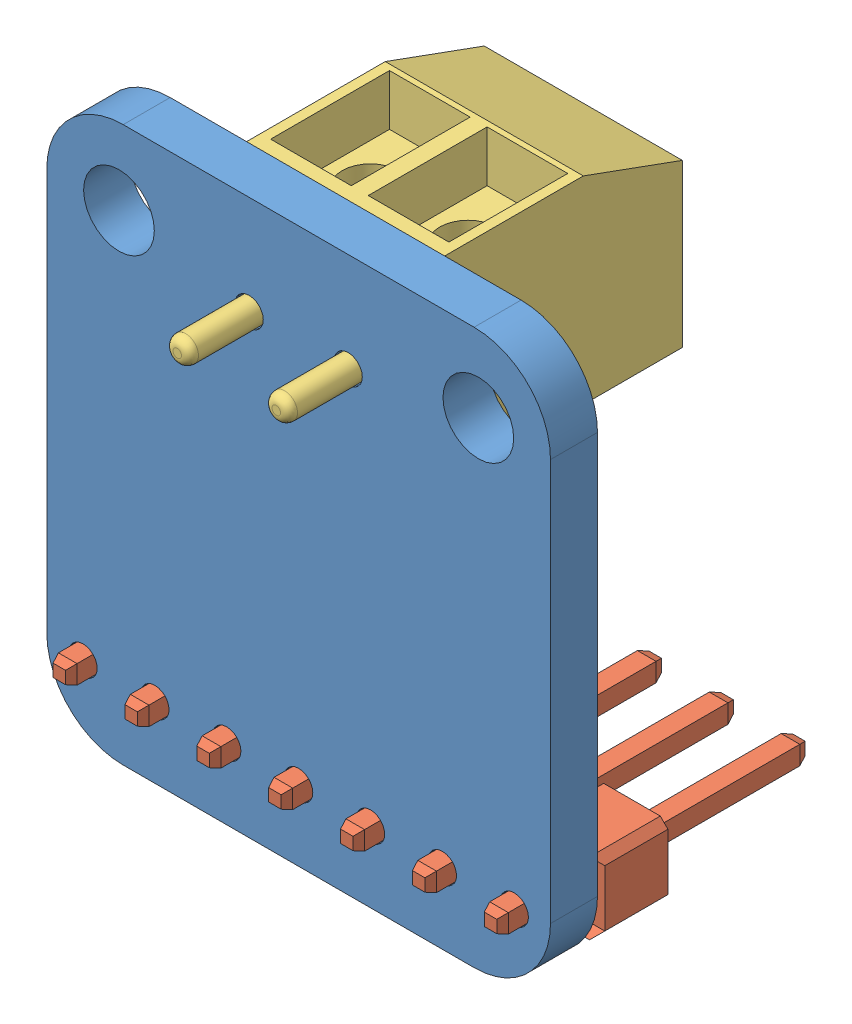
SolidWorks assembly max98357a adafruit, configuration Default. Lengths in mm.
Overall size (17.8 19.6 12.6).
3 component instances, 3 part files, 8 mates.
Components (placement in the parent):
- max98357a adafruit-1: max98357a adafruit [Default] at origin size (17.8 19.6 2.86)
- Header-1: Header [Default] at (7.62 -7.3 0) x (0 -1 0) z (0 0 -1) size (2.54 17.78 10.9)
- 2-Pin-connector-1: 2-Pin-connector [Default] at (0 6.3 0) x (1 0 0) z (0 0 -1) size (7 7 12.6)
Mates (geometry in assembly coordinates):
- Coincident208: coincident: plane of max98357a adafruit-1 through (0 0 0) normal (0 0 -1); line of Header-1 through (-6.62 -8.57 0) axis (-1 0 0)
- Coincident209: coincident aligned: plane of max98357a adafruit-1 through (0 0 0) normal (0 0 -1); plane of Header-1 through (7.62 -7.3 0) normal (0 0 -1)
- Parallel23: parallel aligned: plane of max98357a adafruit-1 through (8.9 -9.8 1.66) normal (0 -1 0); plane of Header-1 through (6.08 -8.57 -2.5) normal (0 -1 0)
- Distance33: distance = 2.5 mm aligned: plane of Header-1; plane of max98357a adafruit-1 through (8.9 -9.8 1.66) normal (0 -1 0)
- Symmetric32: symmetric aligned: plane of max98357a adafruit-1 through (0 0 0) normal (1 0 0); plane of Header-1 through (8.89 -6.3 -2.5) normal (1 0 0); plane of Header-1 through (-8.89 -6.3 -2.5) normal (-1 0 0)
- Coincident210: coincident: plane of max98357a adafruit-1 through (0 0 0) normal (0 0 -1); plane of 2-Pin-connector-1 through (0 6.3 0) normal (0 0 1)
- Concentric1: concentric: cylinder of max98357a adafruit-1 through (1.75 6.3 0) axis (0 0 -1) radius 0.5; cylinder of 2-Pin-connector-1 through (1.75 6.3 4.2) axis (0 0 -1) radius 0.45
- Concentric2: concentric aligned: cylinder of max98357a adafruit-1 through (-1.75 6.3 0) axis (0 0 -1) radius 0.5; cylinder of 2-Pin-connector-1 through (-1.75 6.3 4.2) axis (0 0 -1) radius 0.45
